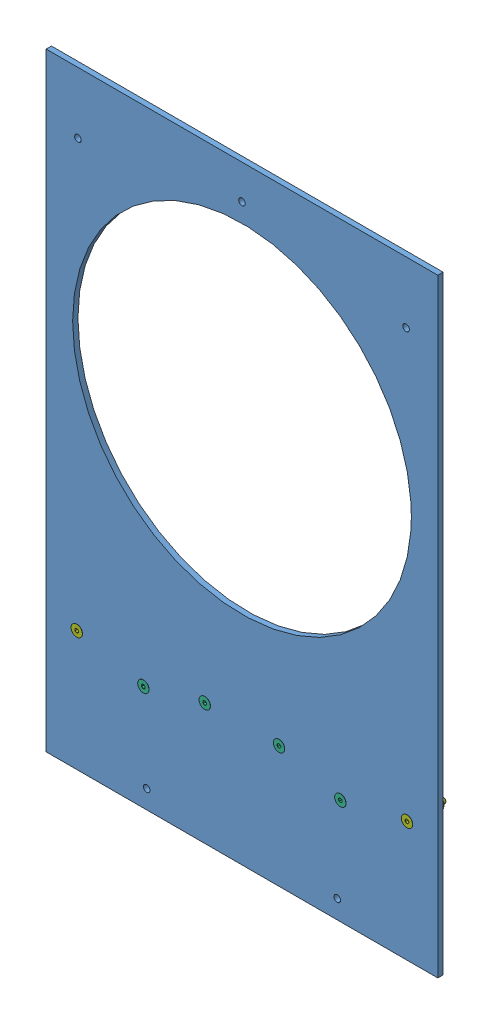
SolidWorks assembly GE-19129, configuration Default. Lengths in mm.
Overall size (469.9 730.25 44.86).
19 component instances, 7 part files, 38 mates.
Components (placement in the parent):
- GE-19125-1: GE-19125 [Default] at origin size (469.9 730.25 6.35)
- GE-19029-1: GE-19029 [Default] at (-12.7 1829.207 0) x (0 0 -1) z (-0.965926 -0.258819 0) size (38.1 38.1 152.4)
- GE-19029-2: GE-19029 [Default] at (159.9071 1789.763 0) x (0 0 -1) z (-0.965926 0.258819 0) size (38.1 38.1 152.4)
- spacer_.257_1_.5-1: spacer_.257_1_.5 [Default] at (-198.12 1799.2459 -25.4) x (-0.923728 -0.383049 0) z (-0.383049 0.923728 0) size (12.7 25.4 12.7)
- spacer_.257_1_.5-2: spacer_.257_1_.5 [Default] at (198.12 1799.2459 -25.4) x (-0.923728 -0.383049 0) z (-0.383049 0.923728 0) size (12.7 25.4 12.7)
- nylock_.25_20-1: nylock_.25_20 [Default] at (198.12 1799.2459 -25.4) x (1 0 0) z (0 1 0) size (11.11 7.94 12.83)
- nylock_.25_20-2: nylock_.25_20 [Default] at (118.1748 1781.2231 -3.175) x (0.987351 0.158553 0) z (-0.158553 0.987351 0) size (11.11 7.94 12.83)
- nylock_.25_20-4: nylock_.25_20 [Default] at (44.5713 1800.9452 -3.175) x (0.959125 0.282984 0) z (-0.282984 0.959125 0) size (11.11 7.94 12.83)
- nylock_.25_20-6: nylock_.25_20 [Default] at (-44.5713 1800.9452 -3.175) x (0.928571 0.371154 0) z (-0.371154 0.928571 0) size (11.11 7.94 12.83)
- nylock_.25_20-8: nylock_.25_20 [Default] at (-118.1748 1781.2231 -3.175) x (0.906989 0.421154 0) z (-0.421154 0.906989 0) size (11.11 7.94 12.83)
- nylock_.25_20-10: nylock_.25_20 [Default] at (-198.12 1799.2459 -25.4) x (0.902849 0.429957 0) z (-0.429957 0.902849 0) size (11.11 7.94 12.83)
- Hook_1_6-1: Hook_1_6 [Default] at (12.7 1829.207 -6.35) x (0.965926 -0.258819 0) z (0 0 1) size (152.4 1.59 25.4)
- Hook_1_6-2: Hook_1_6 [Default] at (-159.9071 1789.763 -6.35) x (0.965926 0.258819 0) z (0 0 1) size (152.4 1.59 25.4)
- flat_hex_.25_20_1-1: flat_hex_.25_20_1 [91253A542] at (-118.1748 1781.2231 6.5545) size (13.49 13.49 25.61)
- flat_hex_.25_20_1-2: flat_hex_.25_20_1 [91253A542] at (-44.5713 1800.9452 6.5545) x (0.987351 0.158553 0) z (0 0 1) size (13.49 13.49 25.61)
- flat_hex_.25_20_1-4: flat_hex_.25_20_1 [91253A542] at (44.5713 1800.9452 6.5545) x (0.959125 0.282984 0) z (0 0 1) size (13.49 13.49 25.61)
- flat_hex_.25_20_1-6: flat_hex_.25_20_1 [91253A542] at (118.1748 1781.2231 6.5545) x (0.928571 0.371154 0) z (0 0 1) size (13.49 13.49 25.61)
- flat_hex_.25_20_1.75-1: flat_hex_.25_20_1.75 [91253A548] at (-198.12 1799.2459 6.5545) size (13.49 13.49 44.66)
- flat_hex_.25_20_1.75-2: flat_hex_.25_20_1.75 [91253A548] at (198.12 1799.2459 6.5545) x (0.987351 0.158553 0) z (0 0 1) size (13.49 13.49 44.66)
Mates (geometry in assembly coordinates):
- Coincident1: coincident: plane of GE-19125-1 through (0 0 0) normal (0 0 -1); plane of spacer_.257_1_.5-2 through (198.12 1799.2459 0) normal (0 0 1)
- Coincident2: coincident: plane of GE-19125-1 through (0 0 0) normal (0 0 -1); plane of spacer_.257_1_.5-1 through (-198.12 1799.2459 0) normal (0 0 1)
- Coincident3: coincident: circle of GE-19125-1; circle of GE-19029-2
- Concentric1: concentric: cylinder of GE-19125-1 through (118.1748 1781.2231 6.35) axis (0 0 1) radius 3.3782; cylinder of GE-19029-2 through (118.1748 1781.2231 0) axis (0 0 1) radius 3.3782
- Coincident4: coincident: circle of GE-19125-1; circle of GE-19029-1
- Concentric2: concentric: cylinder of GE-19125-1 through (-118.1748 1781.2231 6.35) axis (0 0 1) radius 3.3782; cylinder of GE-19029-1 through (-118.1748 1781.2231 0) axis (0 0 1) radius 3.3782
- Concentric4: concentric: cylinder of GE-19125-1 through (198.12 1799.2459 6.35) axis (0 0 1) radius 3.3782; cylinder of spacer_.257_1_.5-2 through (198.12 1799.2459 0) axis (0 0 -1) radius 3.2639
- Concentric5: concentric: cylinder of GE-19125-1 through (-198.12 1799.2459 6.35) axis (0 0 1) radius 3.3782; cylinder of spacer_.257_1_.5-1 through (-198.12 1799.2459 0) axis (0 0 -1) radius 3.2639
- Coincident11: coincident: plane of assembly; plane of assembly; plane of spacer_.257_1_.5-2 through (198.12 1799.2459 -25.4) normal (0 0 -1); plane of nylock_.25_20-1 through (198.12 1799.2459 -25.4) normal (0 0 1)
- Coincident12: coincident: plane of assembly; plane of assembly; plane of GE-19029-2 through (2.839 1792.4053 -3.175) normal (0 0 -1); plane of nylock_.25_20-2 through (118.1748 1781.2231 -3.175) normal (0 0 1)
- Coincident13: coincident: plane of assembly; plane of assembly; plane of GE-19029-2 through (2.839 1792.4053 -3.175) normal (0 0 -1); plane of nylock_.25_20-4 through (44.5713 1800.9452 -3.175) normal (0 0 1)
- Coincident14: coincident: plane of assembly; plane of assembly; plane of GE-19029-1 through (-150.0461 1752.9612 -3.175) normal (0 0 -1); plane of nylock_.25_20-6 through (-44.5713 1800.9452 -3.175) normal (0 0 1)
- Coincident15: coincident: plane of assembly; plane of assembly; plane of GE-19029-1 through (-150.0461 1752.9612 -3.175) normal (0 0 -1); plane of nylock_.25_20-8 through (-118.1748 1781.2231 -3.175) normal (0 0 1)
- Coincident16: coincident: plane of assembly; plane of assembly; plane of spacer_.257_1_.5-1 through (-198.12 1799.2459 -25.4) normal (0 0 -1); plane of nylock_.25_20-10 through (-198.12 1799.2459 -25.4) normal (0 0 1)
- Coincident17: coincident: plane of assembly; plane of assembly; plane of GE-19029-2 through (12.7 1829.207 -38.1) normal (0.258819 0.965926 0); plane of Hook_1_6-1 through (12.7 1829.207 -6.35) normal (-0.258819 -0.965926 0)
- Coincident18: coincident: plane of assembly; plane of assembly; plane of GE-19029-1 through (-159.9071 1789.763 -38.1) normal (-0.258819 0.965926 0); plane of Hook_1_6-2 through (-159.9071 1789.763 -6.35) normal (0.258819 -0.965926 0)
- Coincident19: coincident: plane of assembly; plane of assembly; plane of GE-19029-1 through (-159.9071 1789.763 0) normal (-0.965926 -0.258819 0); plane of Hook_1_6-2 through (-160.318 1791.2964 -6.35) normal (-0.965926 -0.258819 0)
- Coincident20: coincident: plane of assembly; plane of assembly; plane of GE-19029-2 through (159.9071 1789.763 0) normal (0.965926 -0.258819 0); plane of Hook_1_6-1 through (160.318 1791.2964 -6.35) normal (0.965926 -0.258819 0)
- Width1: width: plane of assembly; plane of assembly; plane of assembly; plane of assembly; plane of Hook_1_6-1 through (13.1109 1830.7405 -31.75) normal (0 0 -1); plane of Hook_1_6-1 through (13.1109 1830.7405 -6.35) normal (0 0 1); plane of GE-19029-2 through (11.8782 1826.1402 -38.1) normal (0 0 -1); plane of GE-19029-2 through (12.7 1829.207 0) normal (0 0 1)
- Width2: width: plane of assembly; plane of assembly; plane of assembly; plane of assembly; plane of Hook_1_6-2 through (-160.318 1791.2964 -31.75) normal (0 0 -1); plane of Hook_1_6-2 through (-160.318 1791.2964 -6.35) normal (0 0 1); plane of GE-19029-1 through (-159.0853 1786.6962 -38.1) normal (0 0 -1); plane of GE-19029-1 through (-159.9071 1789.763 0) normal (0 0 1)
- Concentric18: concentric: circle of GE-19125-1; circle of flat_hex_.25_20_1-1
- Coincident22: coincident: cone of GE-19125-1 through (-118.1748 1781.2231 6.35) axis (0 0 -1); cylinder of flat_hex_.25_20_1-1 through (-118.1748 1781.2231 2.4651) axis (0 0 -1) radius 715.585
- Concentric19: concentric: cylinder of assembly; cylinder of assembly; cylinder of nylock_.25_20-8 through (-118.1748 1781.2231 -3.175) axis (0 0 -1) radius 3.175; cylinder of flat_hex_.25_20_1-1 through (-118.1748 1781.2231 -18.8455) axis (0 0 -1) radius 3.175
- Concentric20: concentric: unknown of GE-19125-1; unknown of flat_hex_.25_20_1-2
- Coincident23: coincident: cylinder of GE-19125-1 through (-44.5713 1800.9452 6.35) axis (0 0 -1) radius 715.585; cylinder of flat_hex_.25_20_1-2 through (-44.5713 1800.9452 2.4651) axis (0 0 -1) radius 715.585
- Concentric21: concentric: cylinder of assembly; cylinder of assembly; cylinder of nylock_.25_20-6 through (-44.5713 1800.9452 -3.175) axis (0 0 -1) radius 3.175; cylinder of flat_hex_.25_20_1-2 through (-44.5713 1800.9452 -18.8455) axis (0 0 -1) radius 3.175
- Concentric22: concentric: unknown of GE-19125-1; unknown of flat_hex_.25_20_1-4
- Coincident24: coincident: cylinder of GE-19125-1 through (44.5713 1800.9452 6.35) axis (0 0 -1) radius 715.585; cylinder of flat_hex_.25_20_1-4 through (44.5713 1800.9452 2.4651) axis (0 0 -1) radius 715.585
- Concentric23: concentric: cylinder of assembly; cylinder of assembly; cylinder of nylock_.25_20-4 through (44.5713 1800.9452 -3.175) axis (0 0 -1) radius 3.175; cylinder of flat_hex_.25_20_1-4 through (44.5713 1800.9452 -18.8455) axis (0 0 -1) radius 3.175
- Concentric24: concentric: unknown of GE-19125-1; unknown of flat_hex_.25_20_1-6
- Coincident25: coincident: cylinder of GE-19125-1 through (118.1748 1781.2231 6.35) axis (0 0 -1) radius 715.585; cylinder of flat_hex_.25_20_1-6 through (118.1748 1781.2231 2.4651) axis (0 0 -1) radius 715.585
- Concentric25: concentric: cylinder of assembly; cylinder of assembly; cylinder of nylock_.25_20-2 through (118.1748 1781.2231 -3.175) axis (0 0 -1) radius 3.175; cylinder of flat_hex_.25_20_1-6 through (118.1748 1781.2231 -18.8455) axis (0 0 -1) radius 3.175
- Concentric26: concentric: circle of GE-19125-1; circle of flat_hex_.25_20_1.75-1
- Coincident27: coincident: cylinder of GE-19125-1 through (-198.12 1799.2459 6.35) axis (0 0 -1) radius 715.585; cylinder of flat_hex_.25_20_1.75-1 through (-198.12 1799.2459 2.4651) axis (0 0 -1) radius 715.585
- Concentric27: concentric: cylinder of assembly; cylinder of assembly; cylinder of nylock_.25_20-10 through (-198.12 1799.2459 -25.4) axis (0 0 -1) radius 3.175; cylinder of flat_hex_.25_20_1.75-1 through (-198.12 1799.2459 -37.8955) axis (0 0 -1) radius 3.175
- Concentric28: concentric: unknown of GE-19125-1; unknown of flat_hex_.25_20_1.75-2
- Coincident28: coincident: cylinder of GE-19125-1 through (198.12 1799.2459 6.35) axis (0 0 -1) radius 715.585; cylinder of flat_hex_.25_20_1.75-2 through (198.12 1799.2459 2.4651) axis (0 0 -1) radius 715.585
- Concentric29: concentric: cylinder of assembly; cylinder of assembly; cylinder of nylock_.25_20-1 through (198.12 1799.2459 -25.4) axis (0 0 -1) radius 3.175; cylinder of flat_hex_.25_20_1.75-2 through (198.12 1799.2459 -37.8955) axis (0 0 -1) radius 3.175
